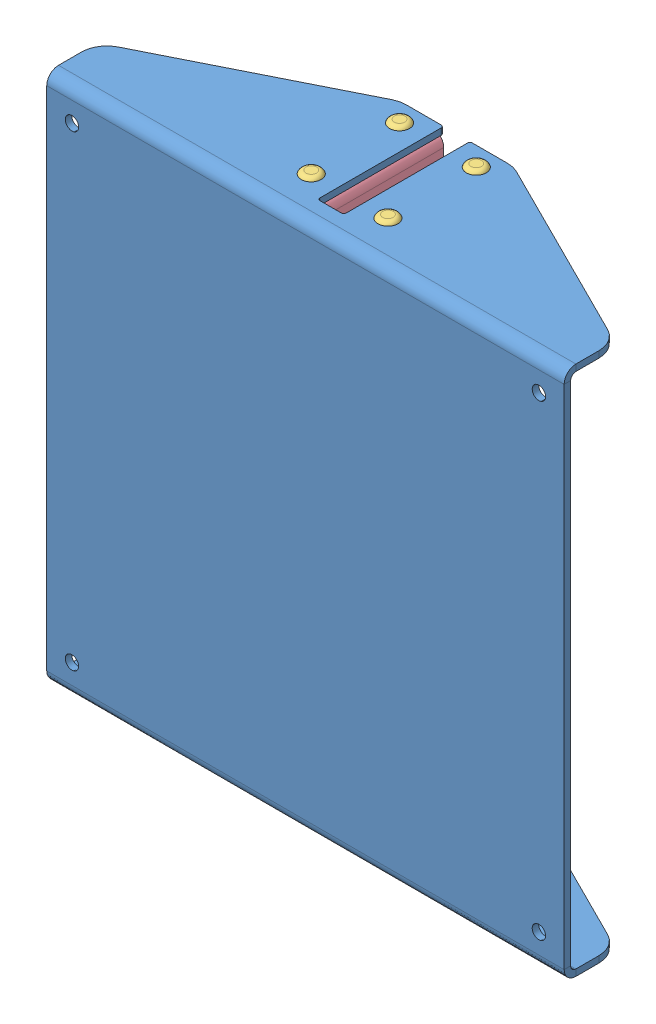
SolidWorks assembly GE-25219, configuration Default. Lengths in mm.
Overall size (260.35 270.08 76.2).
13 component instances, 5 part files, 29 mates.
Components (placement in the parent):
- GE-25219-01-1: GE-25219-01 [Default] at origin size (260.35 266.88 76.2)
- GE-25219-02-2: GE-25219-02 [Default] at (6.604 0 -44.45) x (0 -1 0) z (-1 0 0) size (260.35 63.5 19.05)
- rivet_.1875_.126-.25-1: rivet_.1875_.126-.25 [Default] at (-19.304 133.4389 -66.675) x (-0.837169 0 -0.546944) z (0 1 0) size (10.01 10.01 13.03)
- rivet_.1875_.126-.25-2: rivet_.1875_.126-.25 [Default] at (-19.304 133.4389 -22.225) x (-0.925243 0 -0.379375) z (0 1 0) size (10.01 10.01 13.03)
- rivet_.1875_.126-.25-4: rivet_.1875_.126-.25 [Default] at (19.304 133.4389 -22.225) x (-0.985271 0 -0.170998) z (0 1 0) size (10.01 10.01 13.03)
- rivet_.1875_.126-.25-6: rivet_.1875_.126-.25 [Default] at (19.304 133.4389 -66.675) x (-0.997902 0 0.064746) z (0 1 0) size (10.01 10.01 13.03)
- rivet_.1875_.126-.25-8: rivet_.1875_.126-.25 [Default] at (19.304 -133.4389 -66.675) x (0.953572 0 0.301166) z (0 -1 0) size (10.01 10.01 13.03)
- rivet_.1875_.126-.25-10: rivet_.1875_.126-.25 [Default] at (-19.304 -133.4389 -66.675) x (0.86157 0 0.507639) z (0 -1 0) size (10.01 10.01 13.03)
- rivet_.1875_.126-.25-12: rivet_.1875_.126-.25 [Default] at (19.304 -133.4389 -22.225) x (0.748019 0 0.663677) z (0 -1 0) size (10.01 10.01 13.03)
- rivet_.1875_.126-.25-14: rivet_.1875_.126-.25 [Default] at (-19.304 -133.4389 -22.225) x (0.643589 0 0.765371) z (0 -1 0) size (10.01 10.01 13.03)
- GE-25219-03-1: GE-25219-03 [Default] at (-6.604 0 -44.45) x (0 -1 0) z (1 0 0) size (260.35 63.5 19.05)
- pem_clinchnut_.25_20_.054-1: pem_clinchnut_.25_20_.054 [Default] at (-8.4963 107.95 -44.45) x (-1 0 0) z (0 -0.924225 -0.381849) size (5.69 11.18 11.18)
- pem_clinchnut_.25_20_.054-2: pem_clinchnut_.25_20_.054 [Default] at (-8.4963 -107.95 -44.45) x (-1 0 0) z (0 -0.85199 -0.523557) size (5.69 11.18 11.18)
Mates (geometry in assembly coordinates):
- Coincident1: coincident aligned: plane of GE-25219-01-1 through (0 0 0) normal (0 0 1)
- Coincident2: coincident aligned: plane of GE-25219-01-1 through (0 0 0) normal (0 1 0)
- Coincident3: coincident aligned: plane of GE-25219-01-1 through (0 0 0) normal (1 0 0)
- Coincident5: coincident anti-aligned: plane of GE-25219-01-1 through (0 -130.175 0) normal (0 1 0); plane of GE-25219-02-2 through (6.604 -130.175 -44.45) normal (0 -1 0)
- Concentric2: concentric anti-aligned: cylinder of GE-25219-01-1 through (19.304 133.4389 -66.675) axis (0 1 0) radius 2.4574; cylinder of GE-25219-02-2 through (19.304 -130.175 -66.675) axis (0 -1 0) radius 2.4574
- Concentric5: concentric anti-aligned: cylinder of GE-25219-01-1 through (19.304 133.4389 -22.225) axis (0 1 0) radius 2.4574; cylinder of GE-25219-02-2 through (19.304 -130.175 -22.225) axis (0 -1 0) radius 2.4574
- Concentric7: concentric aligned: cylinder of GE-25219-01-1 through (-19.304 133.4389 -66.675) axis (0 1 0) radius 2.4574; cylinder of rivet_.1875_.126-.25-1 through (-19.304 122.0089 -66.675) axis (0 1 0) radius 2.3813
- Coincident6: coincident anti-aligned: plane of GE-25219-01-1 through (0 133.4389 0) normal (0 1 0); plane of rivet_.1875_.126-.25-1 through (-19.304 133.4389 -66.675) normal (0 -1 0)
- Concentric8: concentric aligned: cylinder of GE-25219-01-1 through (-19.304 133.4389 -22.225) axis (0 1 0) radius 2.4574; cylinder of rivet_.1875_.126-.25-2 through (-19.304 122.0089 -22.225) axis (0 1 0) radius 2.3813
- Coincident7: coincident anti-aligned: plane of GE-25219-01-1 through (0 133.4389 0) normal (0 1 0); plane of rivet_.1875_.126-.25-2 through (-19.304 133.4389 -22.225) normal (0 -1 0)
- Concentric9: concentric aligned: cylinder of GE-25219-01-1 through (19.304 133.4389 -22.225) axis (0 1 0) radius 2.4574; cylinder of rivet_.1875_.126-.25-4 through (19.304 122.0089 -22.225) axis (0 1 0) radius 2.3813
- Coincident8: coincident anti-aligned: plane of GE-25219-01-1 through (0 133.4389 0) normal (0 1 0); plane of rivet_.1875_.126-.25-4 through (19.304 133.4389 -22.225) normal (0 -1 0)
- Concentric10: concentric aligned: cylinder of GE-25219-01-1 through (19.304 133.4389 -66.675) axis (0 1 0) radius 2.4574; cylinder of rivet_.1875_.126-.25-6 through (19.304 122.0089 -66.675) axis (0 1 0) radius 2.3813
- Coincident9: coincident anti-aligned: plane of GE-25219-01-1 through (0 133.4389 0) normal (0 1 0); plane of rivet_.1875_.126-.25-6 through (19.304 133.4389 -66.675) normal (0 -1 0)
- Concentric11: concentric anti-aligned: cylinder of GE-25219-01-1 through (19.304 133.4389 -66.675) axis (0 1 0) radius 2.4574; cylinder of rivet_.1875_.126-.25-8 through (19.304 -122.0089 -66.675) axis (0 -1 0) radius 2.3813
- Coincident10: coincident anti-aligned: plane of GE-25219-01-1 through (0 -133.4389 0) normal (0 -1 0); plane of rivet_.1875_.126-.25-8 through (19.304 -133.4389 -66.675) normal (0 1 0)
- Concentric12: concentric anti-aligned: cylinder of GE-25219-01-1 through (-19.304 133.4389 -66.675) axis (0 1 0) radius 2.4574; cylinder of rivet_.1875_.126-.25-10 through (-19.304 -122.0089 -66.675) axis (0 -1 0) radius 2.3813
- Coincident11: coincident anti-aligned: plane of GE-25219-01-1 through (0 -133.4389 0) normal (0 -1 0); plane of rivet_.1875_.126-.25-10 through (-19.304 -133.4389 -66.675) normal (0 1 0)
- Concentric13: concentric anti-aligned: cylinder of GE-25219-01-1 through (19.304 133.4389 -22.225) axis (0 1 0) radius 2.4574; cylinder of rivet_.1875_.126-.25-12 through (19.304 -122.0089 -22.225) axis (0 -1 0) radius 2.3813
- Coincident12: coincident anti-aligned: plane of GE-25219-01-1 through (0 -133.4389 0) normal (0 -1 0); plane of rivet_.1875_.126-.25-12 through (19.304 -133.4389 -22.225) normal (0 1 0)
- Concentric14: concentric anti-aligned: cylinder of GE-25219-01-1 through (-19.304 133.4389 -22.225) axis (0 1 0) radius 2.4574; cylinder of rivet_.1875_.126-.25-14 through (-19.304 -122.0089 -22.225) axis (0 -1 0) radius 2.3813
- Coincident13: coincident anti-aligned: plane of GE-25219-01-1 through (0 -133.4389 0) normal (0 -1 0); plane of rivet_.1875_.126-.25-14 through (-19.304 -133.4389 -22.225) normal (0 1 0)
- Coincident14: coincident anti-aligned: plane of GE-25219-01-1 through (0 130.175 0) normal (0 -1 0); plane of GE-25219-03-1 through (-6.604 130.175 -44.45) normal (0 1 0)
- Concentric15: concentric anti-aligned: cylinder of rivet_.1875_.126-.25-1 through (-19.304 122.0089 -66.675) axis (0 1 0) radius 2.3813; cylinder of GE-25219-03-1 through (-19.304 -130.175 -66.675) axis (0 -1 0) radius 2.4574
- Concentric16: concentric anti-aligned: cylinder of rivet_.1875_.126-.25-2 through (-19.304 122.0089 -22.225) axis (0 1 0) radius 2.3813; cylinder of GE-25219-03-1 through (-19.304 -130.175 -22.225) axis (0 -1 0) radius 2.4574
- Concentric17: concentric aligned: cylinder of GE-25219-03-1 through (-6.604 107.95 -44.45) axis (1 0 0) radius 4.3656; cylinder of pem_clinchnut_.25_20_.054-1 through (-11.3411 107.95 -44.45) axis (1 0 0) radius 2.4879
- Coincident15: coincident anti-aligned: plane of GE-25219-03-1 through (-9.8679 0 -44.45) normal (-1 0 0); plane of pem_clinchnut_.25_20_.054-1 through (-9.8679 105.3677 -45.5169) normal (1 0 0)
- Concentric18: concentric aligned: cylinder of GE-25219-03-1 through (-6.604 -107.95 -44.45) axis (1 0 0) radius 4.3656; cylinder of pem_clinchnut_.25_20_.054-2 through (-11.3411 -107.95 -44.45) axis (1 0 0) radius 2.4879
- Coincident16: coincident anti-aligned: plane of GE-25219-03-1 through (-9.8679 0 -44.45) normal (-1 0 0); plane of pem_clinchnut_.25_20_.054-2 through (-9.8679 -110.3305 -45.9128) normal (1 0 0)
